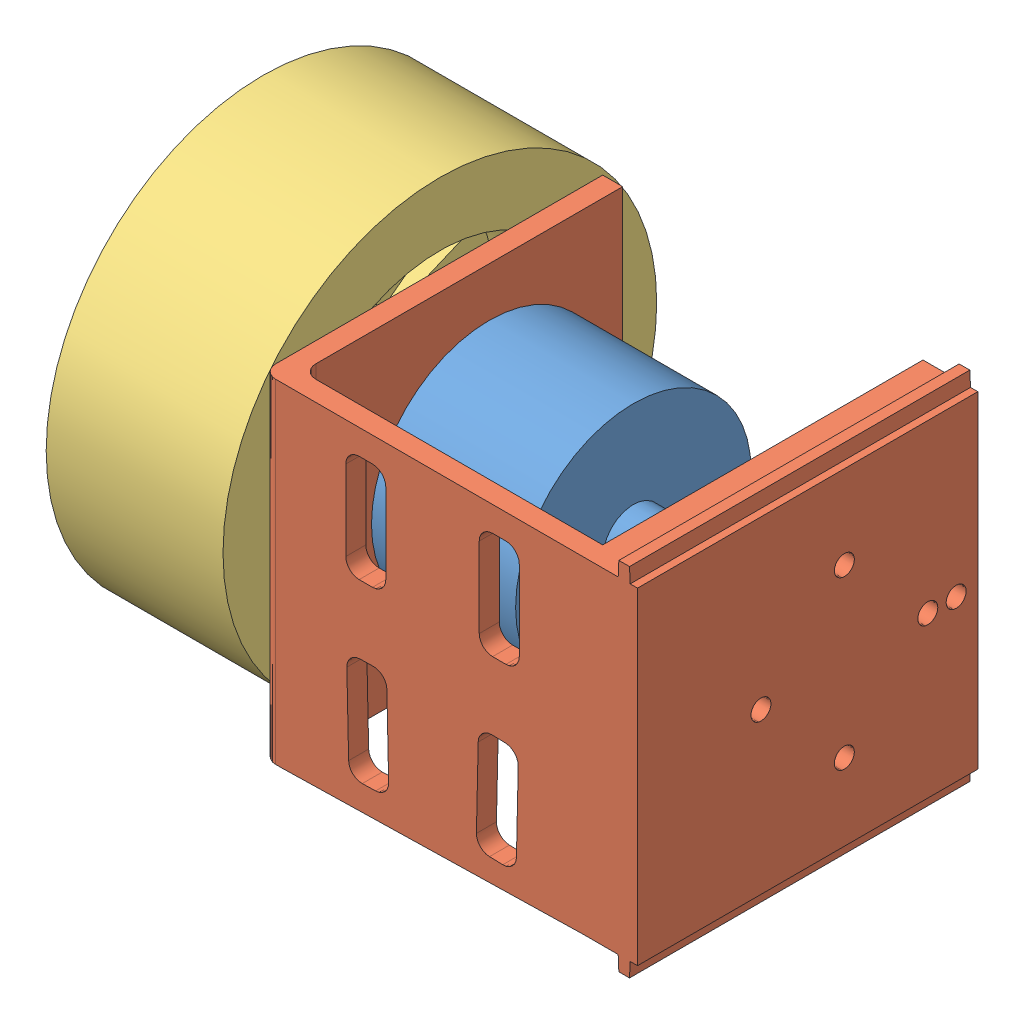
SolidWorks assembly 3525电机和摩擦轮, configuration 默认. Lengths in mm.
Overall size (87.12 88.79 88.79).
4 component instances, 4 part files, 7 mates.
Components (placement in the parent):
- 3525电机-1: 3525电机 [默认] at (4.9249 -1.155 36.6) size (36.6 35.3 35.3)
- 3525电机固定支架-1: 3525电机固定支架 [默认] at (-17.4279 -1.155 36.6) x (0 -1 0) z (1 0 0) size (53 51 56.22)
- 蓝色摩擦轮-1: 蓝色摩擦轮 [默认] at (-48.33 -1.155 36.6) x (0 -0.866025 -0.5) z (0 -0.5 0.866025) size (65 26.5 65)
- 六角联轴器-1: 六角联轴器 [默认] at (-19.83 -1.155 36.6) x (0 0 1) z (-1 0 0) size (14 12.12 17)
Mates (geometry in assembly coordinates):
- 同心1: concentric aligned: cylinder of 3525电机-1 through (-9.4279 -13.655 36.6) axis (-1 0 0) radius 2; cylinder of 3525电机固定支架-1 through (-14.4279 -13.655 36.6) axis (-1 0 0) radius 1.6
- 同心2: concentric anti-aligned: circle of 3525电机-1; circle of 3525电机固定支架-1
- 同心3: concentric anti-aligned: cylinder of 3525电机-1 through (-24.0279 -1.155 36.6) axis (-1 0 0) radius 1.5; cylinder of 六角联轴器-1 through (-32.33 -1.155 36.6) axis (1 0 0) radius 2.5
- 重合6: coincident anti-aligned: plane of 3525电机-1 through (-14.4279 -1.155 36.6) normal (-1 0 0); plane of 3525电机固定支架-1 through (-14.4279 -1.155 36.6) normal (1 0 0)
- 重合7: coincident anti-aligned: plane of 蓝色摩擦轮-1 through (-36.83 -1.155 36.6) normal (1 0 0); plane of 六角联轴器-1 through (-36.83 -1.155 36.6) normal (-1 0 0)
- 重合8: coincident anti-aligned: plane of 蓝色摩擦轮-1 through (-32.83 -7.2172 40.1) normal (0 1 0); plane of 六角联轴器-1 through (-36.83 -7.2172 33.1) normal (0 -1 0)
- 同心4: concentric anti-aligned: circle of 蓝色摩擦轮-1; circle of 六角联轴器-1
